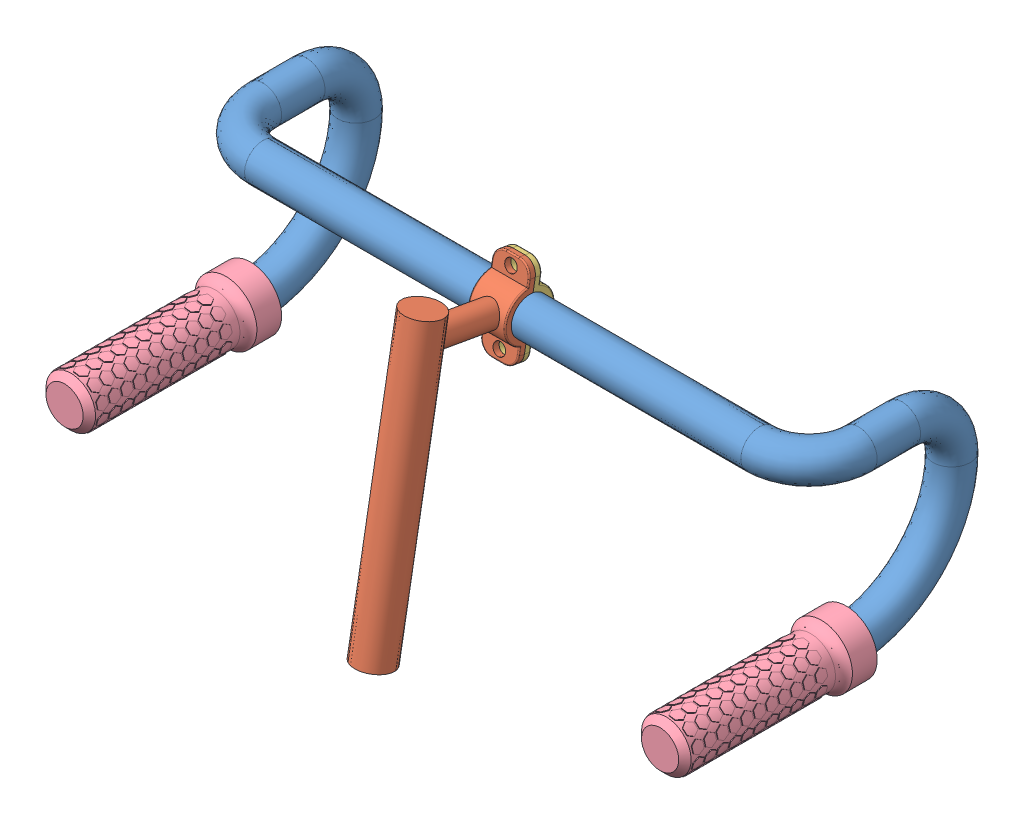
SolidWorks assembly handle, configuration Default. Lengths in mm.
Overall size (530 257.08 256.08).
5 component instances, 4 part files, 11 mates.
Components (placement in the parent):
- handle_new_bar-1: handle_new_bar [Default] at (-27.0743 83.2148 34.4119) size (510 160 195)
- break_parts2-1: break_parts2 [Default] at (-27.0743 97.9869 31.8072) x (0 -0.984808 0.173648) z (-1 0 0) size (245 91 30)
- break_parts-1: break_parts [Default] at (-27.0743 68.4427 37.0166) x (0 0.984808 -0.173648) z (-1 0 0) size (70 20 30)
- griper-1: griper [Default] at (212.9257 -46.7852 4.4119) x (-1 0 0) z (0 1 0) size (50 150 50)
- griper-2: griper [Default] at (-267.0743 -46.7852 4.4119) x (-1 0 0) z (0 1 0) size (50 150 50)
Mates (geometry in assembly coordinates):
- Concentric1: concentric anti-aligned: cylinder of handle_new_bar-1 through (-27.0743 83.2148 34.4119) axis (-1 0 0) radius 15; cylinder of break_parts2-1 through (-42.0743 83.2148 34.4119) axis (1 0 0) radius 15
- Concentric2: concentric anti-aligned: cylinder of handle_new_bar-1 through (-27.0743 83.2148 34.4119) axis (-1 0 0) radius 15; cylinder of break_parts-1 through (-42.0743 83.2148 34.4119) axis (1 0 0) radius 15
- Coincident1: coincident anti-aligned: circle of break_parts2-1; circle of break_parts-1
- Concentric3: concentric anti-aligned: cylinder of handle_new_bar-1 through (212.9257 -46.7852 9.4119) axis (0 0 1) radius 15; cylinder of griper-1 through (212.9257 -46.7852 196.8383) axis (0 0 -1) radius 15
- Distance1: distance = 50 mm anti-aligned: plane of handle_new_bar-1 through (212.9257 -46.7852 99.4119) normal (0 0 1); plane of griper-1 through (212.9257 -46.7852 149.4119) normal (0 0 -1)
- Concentric4: concentric anti-aligned: cylinder of handle_new_bar-1 through (-267.0743 -46.7852 9.4119) axis (0 0 1) radius 15; cylinder of griper-2 through (-267.0743 -46.7852 196.8383) axis (0 0 -1) radius 15
- Distance2: distance = 50 mm anti-aligned: plane of handle_new_bar-1 through (-267.0743 -46.7852 99.4119) normal (0 0 1); plane of griper-2 through (-267.0743 -46.7852 149.4119) normal (0 0 -1)
- Coincident6: coincident anti-aligned: plane of handle_new_bar-1 through (-27.0743 83.2148 34.4119) normal (1 0 0); plane of break_parts2-1 through (-27.0743 97.9869 31.8072) normal (-1 0 0)
- Angle1: planar angle = 2.96706 rad aligned: plane of handle_new_bar-1 through (-27.0743 83.2148 34.4119) normal (0 1 0); plane of break_parts2-1 through (-27.0743 97.9869 31.8072) normal (0 -0.984808 0.173648)
- Parallel2: parallel aligned: plane of handle_new_bar-1 through (-27.0743 83.2148 34.4119) normal (0 1 0); plane of griper-1 through (212.9257 -46.7852 4.4119) normal (0 1 0)
- Parallel3: parallel aligned: plane of handle_new_bar-1 through (-27.0743 83.2148 34.4119) normal (0 1 0); plane of griper-2 through (-267.0743 -46.7852 4.4119) normal (0 1 0)
